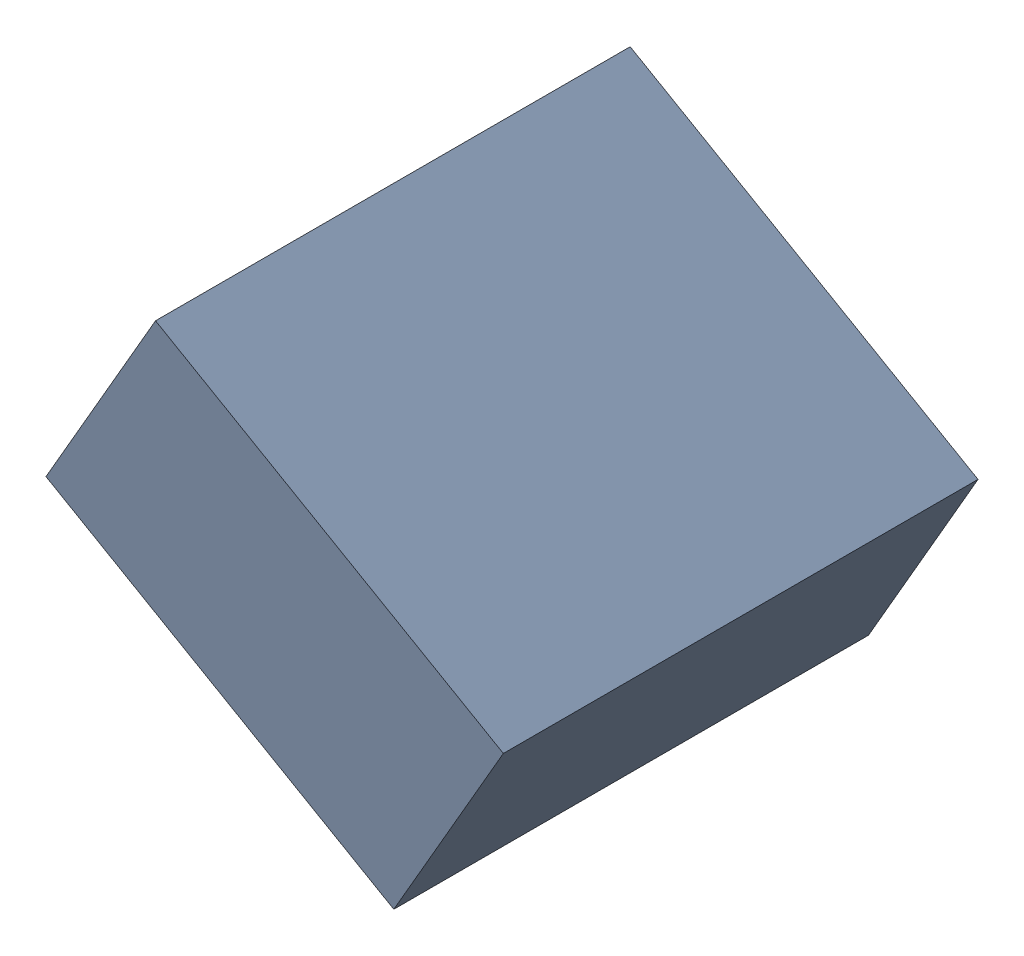
SolidWorks assembly C22_TDA3, configuration Standard. Lengths in mm.
Overall size (1.25 1.07 1.3).
2 component instances, 1 part files, 0 mates.
Components (placement in the parent):
- 885543056-1: 885543056 [Standard] at (47.3334 -24.7074 0) size (1.25 1.07 1.3)
  - Extruded_23-1: Extruded_23 [Standard] at origin size (1.25 1.07 1.3)
